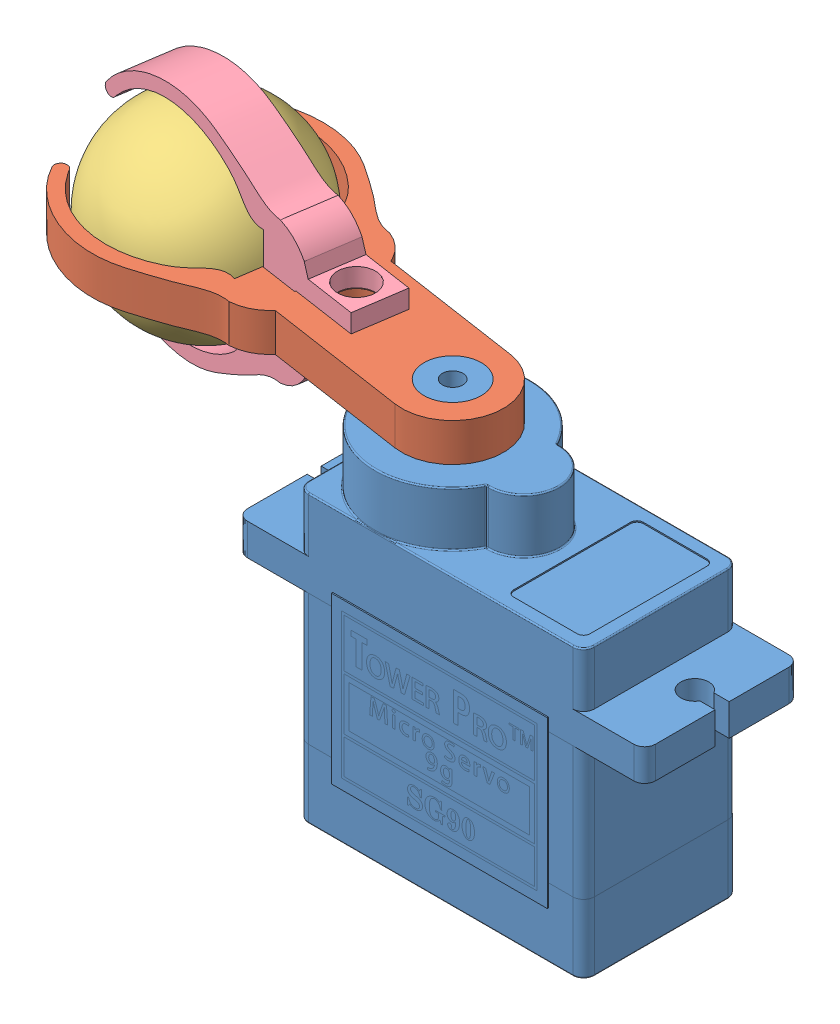
SolidWorks assembly Servo Design, configuration Default. Lengths in mm.
Overall size (52.15 38.4 24.69).
4 component instances, 4 part files, 5 mates.
Components (placement in the parent):
- SG90 - Micro Servo 9g - Tower Pro.1-1: SG90 - Micro Servo 9g - Tower Pro.1 [Peça] at (6.3563 13.9097 26.6005) size (32.1 29.95 12.4)
- Servo Horn-1: Servo Horn [Default] at (-14.2206 30.2097 28.3358) x (0.988981 0 0.14804) z (-0.14804 0 0.988981) size (33.8 3 19.9)
- Ball Weight-1: Ball Weight [Default] at (-21.6948 31.4766 30.6212) size (15 15 15)
- Servo Horn Part 2-1: Servo Horn Part 2 [Default] at (-13.3323 27.7097 22.4019) x (0.988981 0 0.14804) z (0 -1 0) size (23 4 19.9)
Mates (geometry in assembly coordinates):
- Concentric1: concentric aligned: circle of SG90 - Micro Servo 9g - Tower Pro.1-1; circle of Servo Horn-1
- Coincident1: coincident anti-aligned: plane of Servo Horn-1 through (-11.2536 33.2097 28.78) normal (-0.988981 0 -0.14804); plane of Servo Horn Part 2-1 through (-10.9576 27.7097 26.802) normal (0.988981 0 0.14804)
- Width1: width anti-aligned: plane of Servo Horn Part 2-1 through (-13.9245 33.2597 26.3579) normal (0 -1 0); plane of Servo Horn-1 through (-13.9245 30.1597 26.3579) normal (0 1 0); plane of Servo Horn Part 2-1 through (-14.2206 33.2097 28.3358) normal (0 1 0); plane of Servo Horn-1 through (-14.2206 30.2097 28.3358) normal (0 -1 0)
- Width2: width anti-aligned: plane of Servo Horn Part 2-1 through (-13.3323 27.7097 22.4019) normal (0.14804 0 -0.988981); plane of Servo Horn-1 through (-13.9245 27.7097 26.3579) normal (-0.14804 0 0.988981); plane of Servo Horn Part 2-1 through (-13.3249 33.2097 22.3525) normal (-0.14804 0 0.988981); plane of Servo Horn-1 through (-13.9319 33.2097 26.4073) normal (0.14804 0 -0.988981)
- Coincident3: coincident aligned: plane of SG90 - Micro Servo 9g - Tower Pro.1-1 through (1.2063 33.2097 26.6005) normal (0 1 0); plane of Servo Horn-1 through (-14.2206 33.2097 28.3358) normal (0 1 0)
